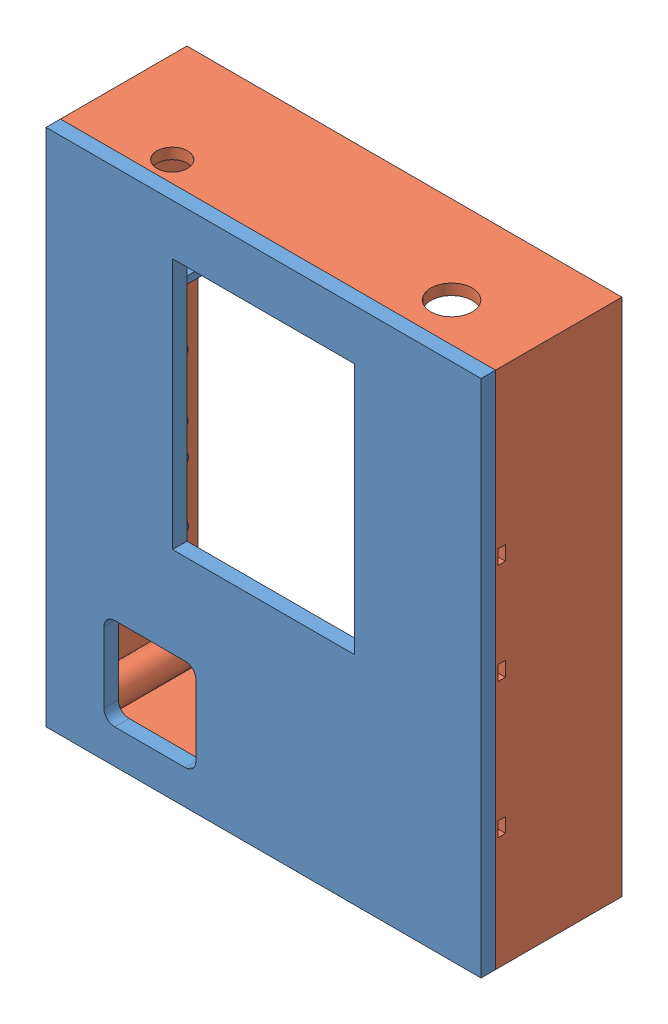
SolidWorks assembly Assem1, configuration Default. Lengths in mm.
Overall size (120.4 143.7 39).
2 component instances, 2 part files, 3 mates.
Components (placement in the parent):
- FrontScreen^CYDModules-1: FrontScreen^CYDModules [Default] at (36.817 27.61 259.3084) size (120.4 143.7 10.5)
- Wall^CYDModules-1: Wall^CYDModules [Default] at (36.817 27.61 259.3084) size (120.4 143.7 35)
Mates (geometry in assembly coordinates):
- Coincident1: coincident: plane of FrontScreen^CYDModules-1 through (36.817 27.61 112.6812) normal (0 0 -1); plane of Wall^CYDModules-1 through (36.817 27.61 112.6812) normal (0 0 1)
- Coincident2: coincident: plane of FrontScreen^CYDModules-1 through (104.5911 152.3617 116.6812) normal (1 0 0); plane of Wall^CYDModules-1 through (104.5911 152.3617 77.6812) normal (1 0 0)
- Coincident3: coincident aligned: plane of FrontScreen^CYDModules-1 through (-15.8089 152.3617 116.6812) normal (0 1 0); plane of Wall^CYDModules-1 through (-15.8089 152.3617 77.6812) normal (0 1 0)
